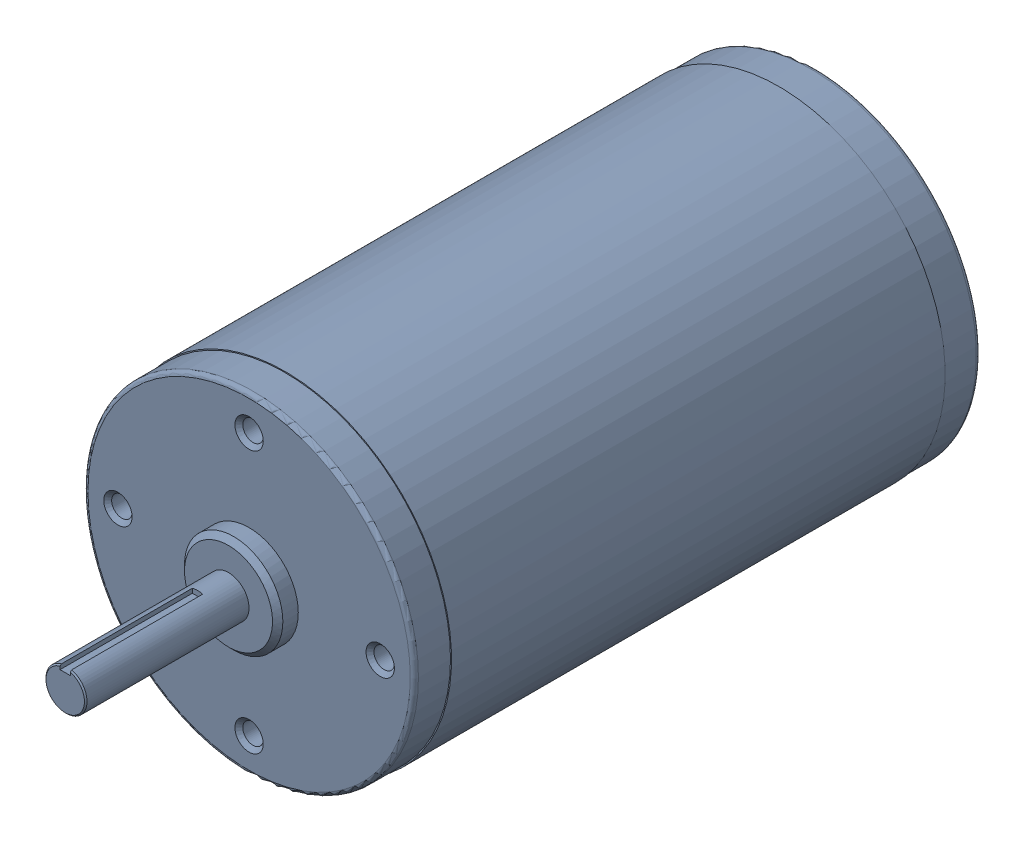
SolidWorks assembly CIM Motor, configuration Default. Lengths in mm.
Overall size (64.41 64.41 149.33).
3 component instances, 2 part files, 0 mates.
Components (placement in the parent):
- CIM motor-1: CIM motor [Default] at origin size (64.41 64.41 149.33)
- 10-24 UNC x 4_ Phillips Pan Head-1: 10-24 UNC x 4_ Phillips Pan Head [Default] at (0 25.4 -98.0336) x (1 0 0) z (0 1 0) size (9.47 105.24 9.47)
- 10-24 UNC x 4_ Phillips Pan Head-2: 10-24 UNC x 4_ Phillips Pan Head [Default] at (0 -25.4 -98.0336) x (-1 0 0) z (0 -1 0) size (9.47 105.24 9.47)
